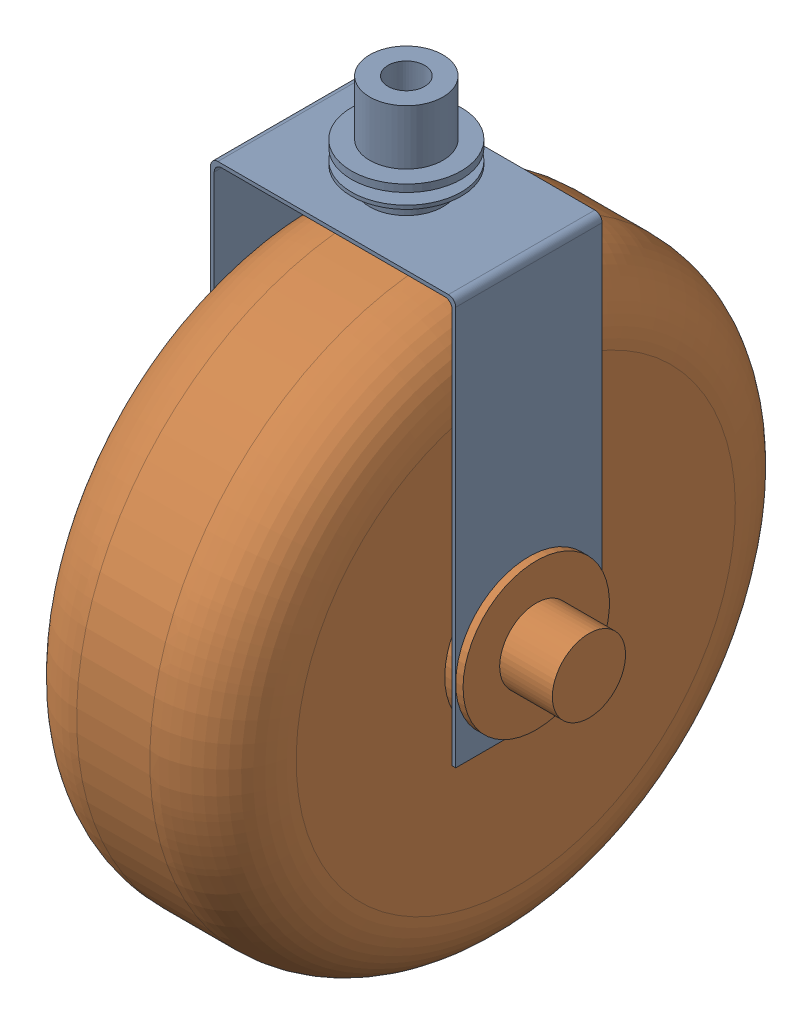
SolidWorks assembly Wheel Assembly 1, configuration Default. Lengths in mm.
Overall size (127 290.5 283.83).
2 component instances, 2 part files, 2 mates.
Components (placement in the parent):
- Wheel Housing-1: Wheel Housing [Default] at (80.6174 -166.1783 -129.8426) size (85.09 173.99 50.8)
- Wheel-1: Wheel [Default] at (80.4904 -166.1783 -104.4426) x (0 0.809055 -0.587733) z (0 0.587733 0.809055) size (203.2 127 203.2)
Mates (geometry in assembly coordinates):
- Concentric2: concentric aligned: cylinder of Wheel Housing-1 through (123.1624 -166.1783 -104.4426) axis (-1 0 0) radius 12.7; cylinder of Wheel-1 through (143.9904 -166.1783 -104.4426) axis (-1 0 0) radius 12.7
- Coincident1: coincident anti-aligned: plane of Wheel Housing-1 through (121.8924 -54.4183 -79.0426) normal (-1 0 0); plane of Wheel-1 through (121.8924 -166.1783 -104.4426) normal (1 0 0)
